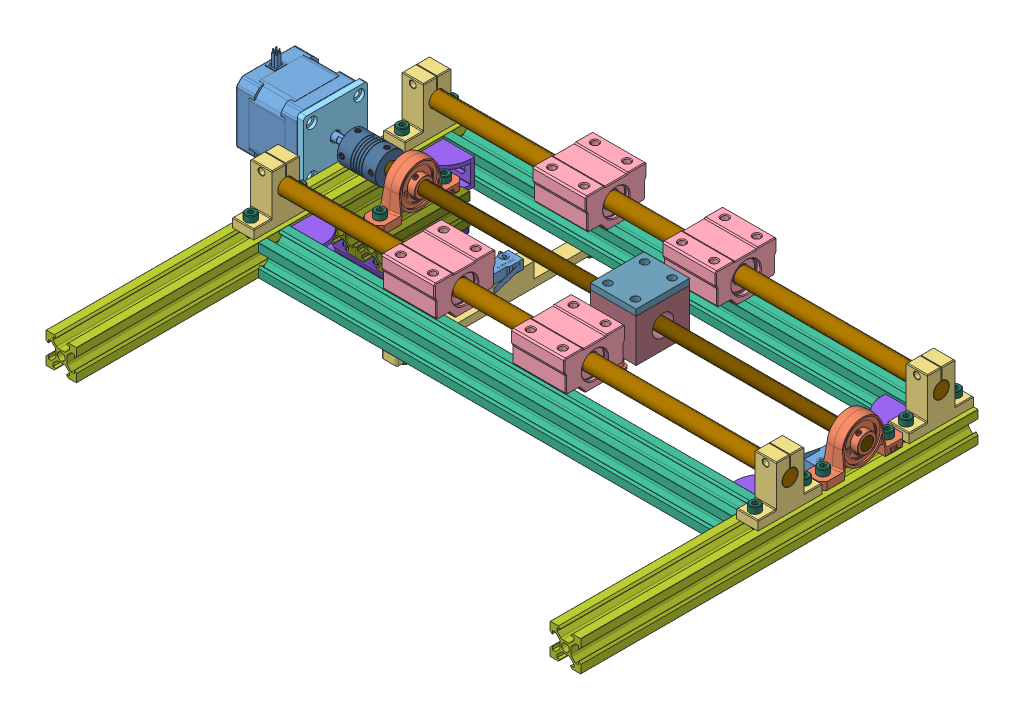
SolidWorks assembly eixox_assembly, configuration Default. Lengths in mm.
Overall size (394 74.2 260).
65 component instances, 21 part files, 147 mates.
Components (placement in the parent):
- motor_nema17_40mm-1: motor_nema17_40mm [По умолчанию] at (-339.1205 -27.1927 21.0547) x (0 0 1) z (0 1 0) size (42.3 62 51.35)
- Pillow Block P08-1: Pillow Block P08 [Default] at (44.8795 -27.1927 21.0547) x (0 0 -1) z (1 0 0) size (55 39.88 14.5)
- suporte_guia_sk10-1: suporte_guia_sk10 [Default] at (-292.1205 -32.4467 79.1336) x (0 0 -1) z (1 0 0) size (42 32.8 14)
- suporte_guia_sk10-2: suporte_guia_sk10 [Default] at (37.8795 -32.4467 -19.8664) x (0 0 -1) z (1 0 0) size (42 32.8 14)
- suporte_guia_sk10-3: suporte_guia_sk10 [Default] at (37.8795 -32.4467 79.1336) x (0 0 -1) z (1 0 0) size (42 32.8 14)
- suporte_guia_sk10-4: suporte_guia_sk10 [Default] at (-292.1205 -32.4467 -19.8664) x (0 0 -1) z (1 0 0) size (42 32.8 14)
- pillow_block_sc10uu-1: pillow_block_sc10uu [По умолчанию] at (-93.3361 -22.1927 -28.4453) x (0 0 1) z (1 0 0) size (40 26 35)
- pillow_block_sc10uu-2: pillow_block_sc10uu [По умолчанию] at (-178.3361 -22.1927 -28.4453) x (0 0 -1) z (-1 0 0) size (40 26 35)
- pillow_block_sc10uu-3: pillow_block_sc10uu [По умолчанию] at (-178.3361 -22.1927 70.5547) x (0 0 -1) z (-1 0 0) size (40 26 35)
- pillow_block_sc10uu-4: pillow_block_sc10uu [По умолчанию] at (-93.3361 -22.1927 70.5547) x (0 0 -1) z (-1 0 0) size (40 26 35)
- eixox_suporte_motor-1: eixox_suporte_motor [Default] at (-295.1205 -62.1927 0.0547) x (0 0 1) z (-1 0 0) size (42 56 4)
- eixox_superior_inferior-1: eixox_superior_inferior [Valor predeterminado] at (-275.1205 -52.1927 -39.4453) x (0 0 -1) z (1 0 0) size (20 20 310)
- eixox_superior_inferior-2: eixox_superior_inferior [Valor predeterminado] at (-275.1205 -52.1927 81.5547) x (0 0 -1) z (1 0 0) size (20 20 310)
- eixox_lateral-1: eixox_lateral [Valor predeterminado] at (-285.1205 -52.1927 -49.4453) size (20 20 260)
- eixox_lateral-2: eixox_lateral [Valor predeterminado] at (44.8795 -52.1927 -49.4453) size (20 20 260)
- cantoneira_perfil_2020-1: cantoneira_perfil_2020 [Varsayılan] at (34.8795 -52.1927 71.5547) x (-1 0 0) z (0 -1 0) size (20.5 20.5 17)
- cantoneira_perfil_2020-2: cantoneira_perfil_2020 [Varsayılan] at (-275.1205 -52.1927 71.5547) x (1 0 0) z (0 1 0) size (20.5 20.5 17)
- cantoneira_perfil_2020-3: cantoneira_perfil_2020 [Varsayılan] at (34.8795 -52.1927 -29.4453) x (-1 0 0) z (0 1 0) size (20.5 20.5 17)
- cantoneira_perfil_2020-4: cantoneira_perfil_2020 [Varsayılan] at (-275.1205 -52.1927 -29.4453) x (1 0 0) z (0 -1 0) size (20.5 20.5 17)
- eixox_eixo_linear-1: eixox_eixo_linear [Default] at (-292.1205 -22.1927 -28.4453) x (0 0.688665 0.725079) z (1 0 0) size (10 10 344)
- eixox_eixo_linear-2: eixox_eixo_linear [Default] at (-292.1205 -22.1927 70.5547) x (0 0 -1) z (1 0 0) size (10 10 344)
- Acople Flexible-2: Acople Flexible [Predeterminado] at (-284.1205 -28.6361 20.2939) x (0 -0.997299 0.073448) z (1 0 0) size (20.77 20.77 25)
  - Acople FlexibleSLDPRT-1: Acople FlexibleSLDPRT [Predeterminado] at (-1.3837 -0.8648 0) size (20.77 20.77 25)
  - socket set screw cone point_am-7: socket set screw cone point_am [B18.3.6M - M3 x 0.5 x 6 Hex Socket Cone Pt. SS --N] at (-11.2647 -0.8648 22) x (1 0 0) z (0 -0.164849 0.986319) size (6 3 3)
  - socket set screw cone point_am-8: socket set screw cone point_am [B18.3.6M - M3 x 0.5 x 6 Hex Socket Cone Pt. SS --N] at (-11.1909 -0.8648 3) x (1 0 0) z (0 0.00677 0.999977) size (6 3 3)
  - socket set screw cone point_am-9: socket set screw cone point_am [B18.3.6M - M3 x 0.5 x 6 Hex Socket Cone Pt. SS --N] at (-1.3837 -10.7654 3) x (0 1 0) z (-0.345086 0 0.938571) size (6 3 3)
  - socket set screw cone point_am-10: socket set screw cone point_am [B18.3.6M - M3 x 0.5 x 6 Hex Socket Cone Pt. SS --N] at (-1.3837 -10.5992 22) x (0 1 0) z (-0.865685 0 0.500588) size (6 3 3)
- castanha_tr8_2mm-2: castanha_tr8_2mm [Valor predeterminado] at (-106.8361 -27.1927 21.0547) x (0 -0.083617 0.996498) z (0 -0.996498 -0.083617) size (22 13.71 22)
- suporte_castanha_tr8-2: suporte_castanha_tr8 [Default] at (-80.8361 -41.1927 38.5547) x (0 0 -1) z (0 1 0) size (35 30 28)
- eixox_espacador_castanha-2: eixox_espacador_castanha [Default] at (-80.8361 -13.1927 38.5547) x (0 0 -1) z (0 1 0) size (35 30 4)
- socket head cap screw_am-1: socket head cap screw_am [B18.3.1M - 4 x 0.7 x 10 Hex SHCS -- 10NHX] at (-285.1205 -32.1927 -44.4453) x (0 -1 0) z (0 0 1) size (14 7 7)
- socket head cap screw_am-2: socket head cap screw_am [B18.3.1M - 4 x 0.7 x 10 Hex SHCS -- 10NHX] at (-285.1205 -32.1927 -12.4453) x (0 -1 0) z (0 0 1) size (14 7 7)
- socket head cap screw_am-3: socket head cap screw_am [B18.3.1M - 4 x 0.7 x 10 Hex SHCS -- 10NHX] at (-285.1205 -32.1927 54.5547) x (0 -1 0) z (0 0 1) size (14 7 7)
- socket head cap screw_am-4: socket head cap screw_am [B18.3.1M - 4 x 0.7 x 10 Hex SHCS -- 10NHX] at (-285.1205 -32.1927 86.5547) x (0 -1 0) z (0 0 1) size (14 7 7)
- socket head cap screw_am-5: socket head cap screw_am [B18.3.1M - 4 x 0.7 x 10 Hex SHCS -- 10NHX] at (44.8795 -32.1927 86.5547) x (0 -1 0) z (0 0 1) size (14 7 7)
- socket head cap screw_am-6: socket head cap screw_am [B18.3.1M - 4 x 0.7 x 10 Hex SHCS -- 10NHX] at (44.8795 -32.1927 54.5547) x (0 -1 0) z (0 0 1) size (14 7 7)
- socket head cap screw_am-7: socket head cap screw_am [B18.3.1M - 4 x 0.7 x 10 Hex SHCS -- 10NHX] at (44.8795 -33.1927 42.0547) x (0 -1 0) z (0 0 1) size (14 7 7)
- socket head cap screw_am-8: socket head cap screw_am [B18.3.1M - 4 x 0.7 x 10 Hex SHCS -- 10NHX] at (44.8795 -33.1927 0.0547) x (0 -1 0) z (0 0 1) size (14 7 7)
- socket head cap screw_am-9: socket head cap screw_am [B18.3.1M - 4 x 0.7 x 10 Hex SHCS -- 10NHX] at (44.8795 -32.1927 -12.4453) x (0 -1 0) z (0 0 1) size (14 7 7)
- socket head cap screw_am-10: socket head cap screw_am [B18.3.1M - 4 x 0.7 x 10 Hex SHCS -- 10NHX] at (44.8795 -32.1927 -44.4453) x (0 -1 0) z (0 0 1) size (14 7 7)
- socket head cap screw_am-11: socket head cap screw_am [B18.3.1M - 4 x 0.7 x 10 Hex SHCS -- 10NHX] at (-303.1205 -52.1927 10.5547) size (14 7 7)
- socket head cap screw_am-12: socket head cap screw_am [B18.3.1M - 4 x 0.7 x 10 Hex SHCS -- 10NHX] at (-303.1205 -52.1927 31.5547) size (14 7 7)
- eixox_perfil_suporte_mancal-1: eixox_perfil_suporte_mancal [Valor predeterminado] at (-265.1205 -52.1927 -6.9034) size (20 20 55)
- eixox_perfil_suporte_mancal-2: eixox_perfil_suporte_mancal [Valor predeterminado] at (-245.1205 -52.1927 -6.9034) size (20 20 55)
- Pillow Block P08-2: Pillow Block P08 [Default] at (-245.1205 -27.1927 21.0547) x (0 0 -1) z (1 0 0) size (55 39.88 14.5)
- eixox_chapa_suporte_mancal-1: eixox_chapa_suporte_mancal [Default] at (-295.1205 -66.1927 38.0966) x (0 0 1) z (0 1 0) size (10 60 4)
- eixox_chapa_suporte_mancal-2: eixox_chapa_suporte_mancal [Default] at (-295.1205 -62.1927 3.0966) x (0 0 -1) z (0 -1 0) size (10 60 4)
- socket head cap screw_am-15: socket head cap screw_am [B18.3.1M - 4 x 0.7 x 10 Hex SHCS -- 10NHX] at (-285.1205 -70.1927 -1.9034) x (0 1 0) z (0 0 1) size (14 7 7)
- socket head cap screw_am-16: socket head cap screw_am [B18.3.1M - 4 x 0.7 x 10 Hex SHCS -- 10NHX] at (-265.1205 -70.1927 -1.9034) x (0 1 0) z (0 0 1) size (14 7 7)
- socket head cap screw_am-17: socket head cap screw_am [B18.3.1M - 4 x 0.7 x 10 Hex SHCS -- 10NHX] at (-245.1205 -70.1927 -1.9034) x (0 1 0) z (0 0 1) size (14 7 7)
- socket head cap screw_am-18: socket head cap screw_am [B18.3.1M - 4 x 0.7 x 10 Hex SHCS -- 10NHX] at (-285.1205 -70.1927 43.0966) x (0 1 0) z (0 0 1) size (14 7 7)
- socket head cap screw_am-19: socket head cap screw_am [B18.3.1M - 4 x 0.7 x 10 Hex SHCS -- 10NHX] at (-265.1205 -70.1927 43.0966) x (0 1 0) z (0 0 1) size (14 7 7)
- socket head cap screw_am-20: socket head cap screw_am [B18.3.1M - 4 x 0.7 x 10 Hex SHCS -- 10NHX] at (-245.1205 -70.1927 43.0966) x (0 1 0) z (0 0 1) size (14 7 7)
- eixox_fuso-2: eixox_fuso [Default] at (-267.1705 -27.1927 21.0547) x (0 0.249209 0.96845) z (1 0 0) size (8 8 320)
- socket head cap screw_am-21: socket head cap screw_am [B18.3.1M - 4 x 0.7 x 10 Hex SHCS -- 10NHX] at (-245.1205 -33.1927 42.0547) x (0 -1 0) z (0 0 1) size (14 7 7)
- socket head cap screw_am-22: socket head cap screw_am [B18.3.1M - 4 x 0.7 x 10 Hex SHCS -- 10NHX] at (-245.1205 -33.1927 0.0547) x (0 -1 0) z (0 0 1) size (14 7 7)
- switch_fim_de_curso_KW11-3Z-5-1: switch_fim_de_curso_KW11-3Z-5 [Default] at (31.8955 -45.9927 31.9487) x (0 0 -1) z (-1 0 0) size (25.09 6.4 19.9)
- pan slot head_am-1: pan slot head_am [B18.6.7M - M3 x 0.5 x 20 Slotted PHMS --20N] at (-95.8361 -53.5927 33.5547) x (0 1 0) z (0 0 1) size (22.48 5.6 5.6)
- eixox_suporte_switch_fim_curso-1: eixox_suporte_switch_fim_curso [Default] at (22.7773 -62.1927 -49.4453) x (1 0 0) z (0 -1 0) size (10 141 15)
- eixox_suporte_switch_fim_curso-2: eixox_suporte_switch_fim_curso [Default] at (-184.407 -62.1927 91.5547) x (-1 0 0) z (0 -1 0) size (10 141 15)
- switch_fim_de_curso_KW11-3Z-5-2: switch_fim_de_curso_KW11-3Z-5 [Default] at (-193.5252 -51.9927 30.0606) x (0 0 -1) z (1 0 0) size (25.09 6.4 19.9)
- socket head cap screw_am-23: socket head cap screw_am [B18.3.1M - 4 x 0.7 x 10 Hex SHCS -- 10NHX] at (27.7773 -71.1927 -39.4453) x (0 1 0) z (0 0 1) size (14 7 7)
- socket head cap screw_am-24: socket head cap screw_am [B18.3.1M - 4 x 0.7 x 10 Hex SHCS -- 10NHX] at (27.7773 -71.1927 81.5547) x (0 1 0) z (0 0 1) size (14 7 7)
- socket head cap screw_am-25: socket head cap screw_am [B18.3.1M - 4 x 0.7 x 10 Hex SHCS -- 10NHX] at (-189.407 -71.1927 -39.4453) x (0 1 0) z (0 0 1) size (14 7 7)
- socket head cap screw_am-26: socket head cap screw_am [B18.3.1M - 4 x 0.7 x 10 Hex SHCS -- 10NHX] at (-189.407 -71.1927 81.5547) x (0 1 0) z (0 0 1) size (14 7 7)
Mates (geometry in assembly coordinates):
- Coincident9: coincident aligned: circle of suporte_guia_sk10-1; cylinder of suporte_guia_sk10-3 through (37.8795 -22.1927 70.5547) axis (1 0 0) radius 5
- Coincident11: coincident aligned: plane of suporte_guia_sk10-1 through (-278.1205 -36.1927 91.5547) normal (0 0 1); plane of suporte_guia_sk10-3 through (51.8795 -36.1927 91.5547) normal (0 0 1)
- Concentric5: concentric aligned: cylinder of suporte_guia_sk10-1 through (-292.1205 -22.1927 70.5547) axis (1 0 0) radius 5; cylinder of pillow_block_sc10uu-4 through (-107.8361 -22.1927 70.5547) axis (1 0 0) radius 5
- Concentric6: concentric aligned: cylinder of suporte_guia_sk10-1 through (-292.1205 -22.1927 70.5547) axis (1 0 0) radius 5; cylinder of pillow_block_sc10uu-3 through (-192.8361 -22.1927 70.5547) axis (1 0 0) radius 5
- Concentric7: concentric aligned: cylinder of suporte_guia_sk10-4 through (-292.1205 -22.1927 -28.4453) axis (1 0 0) radius 5; cylinder of pillow_block_sc10uu-2 through (-192.8361 -22.1927 -28.4453) axis (1 0 0) radius 5
- Coincident18: coincident aligned: plane of pillow_block_sc10uu-3 through (-195.8361 -9.1927 82.0024) normal (0 1 0); plane of pillow_block_sc10uu-4 through (-110.8361 -9.1927 82.0024) normal (0 1 0)
- Coincident19: coincident aligned: plane of pillow_block_sc10uu-1 through (-75.8361 -9.1927 -16.1337) normal (0 1 0); plane of pillow_block_sc10uu-2 through (-195.8361 -9.1927 -16.9976) normal (0 1 0)
- Concentric9: concentric aligned: cylinder of motor_nema17_40mm-1 through (-277.1205 -27.1927 21.0547) axis (-1 0 0) radius 2.5; circle of eixox_suporte_motor-1
- Coincident20: coincident anti-aligned: plane of motor_nema17_40mm-1 through (-299.1205 -27.1927 21.0547) normal (1 0 0); plane of eixox_suporte_motor-1 through (-299.1205 -62.1927 0.0547) normal (-1 0 0)
- Coincident21: coincident aligned: plane of motor_nema17_40mm-1 through (-299.1205 -6.1927 21.0547) normal (0 1 0); plane of eixox_suporte_motor-1 through (-299.1205 -6.1927 4.6831) normal (0 1 0)
- Coincident23: coincident aligned: plane of eixox_superior_inferior-1 through (34.8795 -61.9927 -49.4453) normal (0 0 -1); plane of eixox_lateral-1 through (-288.7034 -60.8927 -49.4453) normal (0 0 -1)
- Coincident37: coincident aligned: plane of eixox_superior_inferior-1 through (34.8795 -61.9927 -49.4453) normal (0 0 -1); plane of eixox_lateral-1 through (-288.7034 -60.8927 -49.4453) normal (0 0 -1)
- Coincident38: coincident anti-aligned: plane of eixox_superior_inferior-1 through (-275.1205 -60.8927 -35.8625) normal (-1 0 0); plane of eixox_lateral-1 through (-275.1205 -42.3927 210.5547) normal (1 0 0)
- Coincident39: coincident aligned: plane of eixox_superior_inferior-1 through (34.8795 -61.9927 -49.4453) normal (0 0 -1); plane of eixox_lateral-1 through (-288.7034 -60.8927 -49.4453) normal (0 0 -1)
- Coincident40: coincident aligned: plane of eixox_superior_inferior-1 through (34.8795 -42.1927 -44.0453) normal (0 1 0); plane of eixox_lateral-1 through (-280.5205 -42.1927 210.5547) normal (0 1 0)
- Coincident41: coincident aligned: plane of eixox_superior_inferior-1 through (34.8795 -42.1927 -44.0453) normal (0 1 0); plane of eixox_lateral-2 through (40.2795 -42.1927 210.5547) normal (0 1 0)
- Coincident42: coincident anti-aligned: plane of eixox_superior_inferior-1 through (34.8795 -60.8927 -35.8625) normal (1 0 0); plane of eixox_lateral-2 through (34.8795 -42.3927 210.5547) normal (-1 0 0)
- Coincident43: coincident aligned: plane of eixox_superior_inferior-1 through (34.8795 -61.9927 -49.4453) normal (0 0 -1); plane of eixox_lateral-2 through (41.2966 -60.8927 -49.4453) normal (0 0 -1)
- Coincident44: coincident anti-aligned: plane of eixox_superior_inferior-2 through (34.8795 -60.8927 85.1375) normal (1 0 0); plane of eixox_lateral-2 through (34.8795 -61.9927 210.5547) normal (-1 0 0)
- Coincident45: coincident aligned: plane of eixox_superior_inferior-2 through (34.8795 -42.1927 76.9547) normal (0 1 0); plane of eixox_lateral-2 through (40.2795 -42.1927 210.5547) normal (0 1 0)
- Distance2: distance = 3 mm aligned: plane of suporte_guia_sk10-1 through (-292.1205 -32.4467 79.1336) normal (-1 0 0); plane of eixox_lateral-1 through (-295.1205 -42.3927 210.5547) normal (-1 0 0)
- Coincident47: coincident aligned: plane of suporte_guia_sk10-1 through (-292.1205 -32.4467 79.1336) normal (-1 0 0); plane of suporte_guia_sk10-4 through (-292.1205 -32.4467 -19.8664) normal (-1 0 0)
- Coincident51: coincident anti-aligned: plane of suporte_guia_sk10-3 through (51.8795 -42.1927 91.5547) normal (0 -1 0); plane of eixox_lateral-2 through (49.4795 -42.1927 210.5547) normal (0 1 0)
- Coincident57: coincident anti-aligned: plane of suporte_guia_sk10-4 through (-278.1205 -42.1927 -7.4453) normal (0 -1 0); plane of eixox_lateral-1 through (-280.5205 -42.1927 210.5547) normal (0 1 0)
- Coincident58: coincident anti-aligned: plane of suporte_guia_sk10-2 through (51.8795 -42.1927 -7.4453) normal (0 -1 0); plane of eixox_lateral-2 through (49.4795 -42.1927 210.5547) normal (0 1 0)
- Concentric11: concentric anti-aligned: cylinder of pillow_block_sc10uu-1 through (-78.8361 -22.1927 -28.4453) axis (-1 0 0) radius 5; cylinder of pillow_block_sc10uu-2 through (-192.8361 -22.1927 -28.4453) axis (1 0 0) radius 5
- Concentric12: concentric anti-aligned: cylinder of suporte_guia_sk10-2 through (37.8795 -22.1927 -28.4453) axis (1 0 0) radius 5; cylinder of pillow_block_sc10uu-1 through (-78.8361 -22.1927 -28.4453) axis (-1 0 0) radius 5
- Coincident59: coincident aligned: plane of suporte_guia_sk10-2 through (51.8795 -32.4467 -19.8664) normal (1 0 0); plane of suporte_guia_sk10-3 through (51.8795 -32.4467 79.1336) normal (1 0 0)
- Distance4: distance = 3 mm aligned: plane of suporte_guia_sk10-2 through (51.8795 -32.4467 -19.8664) normal (1 0 0); plane of eixox_lateral-2 through (54.8795 -42.3927 210.5547) normal (1 0 0)
- Coincident61: coincident anti-aligned: plane of eixox_suporte_motor-1 through (-295.1205 -62.1927 0.0547) normal (1 0 0); plane of eixox_lateral-1 through (-295.1205 -61.9927 210.5547) normal (-1 0 0)
- Coincident62: coincident aligned: plane of eixox_suporte_motor-1 through (-299.1205 -62.1927 0.0547) normal (0 -1 0); plane of eixox_lateral-1 through (-289.7205 -62.1927 210.5547) normal (0 -1 0)
- Coincident65: coincident anti-aligned: plane of Pillow Block P08-1 through (44.8795 -42.1927 21.0547) normal (0 -1 0); plane of eixox_lateral-2 through (49.4795 -42.1927 210.5547) normal (0 1 0)
- Distance5: distance = 3.5 mm aligned: plane of Pillow Block P08-1 through (51.3795 -27.1927 21.0547) normal (1 0 0); plane of eixox_lateral-2 through (54.8795 -42.3927 210.5547) normal (1 0 0)
- Coincident69: coincident aligned: plane of pillow_block_sc10uu-2 through (-195.8361 -9.1927 -40.7569) normal (0 1 0); plane of pillow_block_sc10uu-3 through (-195.8361 -9.1927 58.2431) normal (0 1 0)
- Coincident70: coincident aligned: plane of pillow_block_sc10uu-1 through (-75.8361 -9.1927 -39.893) normal (0 1 0); plane of pillow_block_sc10uu-2 through (-195.8361 -9.1927 -40.7569) normal (0 1 0)
- Coincident72: coincident aligned: plane of suporte_guia_sk10-2 through (51.8795 -36.1927 -49.4453) normal (0 0 -1); plane of eixox_lateral-2 through (41.2966 -60.8927 -49.4453) normal (0 0 -1)
- Coincident73: coincident aligned: plane of pillow_block_sc10uu-1 through (-75.8361 -22.1927 -28.4453) normal (1 0 0); plane of pillow_block_sc10uu-4 through (-75.8361 -22.1927 70.5547) normal (1 0 0)
- Coincident74: coincident aligned: plane of pillow_block_sc10uu-2 through (-160.8361 -22.1927 -28.4453) normal (1 0 0); plane of pillow_block_sc10uu-3 through (-160.8361 -22.1927 70.5547) normal (1 0 0)
- Concentric15: concentric aligned: cylinder of motor_nema17_40mm-1 through (-277.1205 -27.1927 21.0547) axis (-1 0 0) radius 2.5; cylinder of Pillow Block P08-1 through (36.6423 -27.1927 21.0547) axis (-1 0 0) radius 4
- Distance7: distance = 1 mm anti-aligned: plane of suporte_guia_sk10-2 through (51.8795 -36.1927 -7.4453) normal (0 0 1); plane of Pillow Block P08-1 through (51.3795 -27.1927 -6.4453) normal (0 0 -1)
- Distance8: distance = 1 mm anti-aligned: plane of suporte_guia_sk10-3 through (51.8795 -36.1927 49.5547) normal (0 0 -1); plane of Pillow Block P08-1 through (51.3795 -27.1927 48.5547) normal (0 0 1)
- Coincident77: coincident anti-aligned: plane of eixox_lateral-2 through (34.8795 -42.3927 210.5547) normal (-1 0 0); plane of cantoneira_perfil_2020-3 through (34.8795 -43.6927 -29.4453) normal (1 0 0)
- Coincident79: coincident anti-aligned: plane of eixox_superior_inferior-1 through (34.8795 -42.3927 -29.4453) normal (0 0 1); plane of cantoneira_perfil_2020-3 through (14.3795 -43.6927 -29.4453) normal (0 0 -1)
- Coincident80: coincident aligned: plane of cantoneira_perfil_2020-3 through (34.8795 -43.6927 -29.4453) normal (0 1 0); plane of cantoneira_perfil_2020-4 through (-275.1205 -43.6927 -29.4453) normal (0 1 0)
- Coincident81: coincident anti-aligned: plane of eixox_lateral-1 through (-275.1205 -42.3927 210.5547) normal (1 0 0); plane of cantoneira_perfil_2020-4 through (-275.1205 -60.6927 -29.4453) normal (-1 0 0)
- Coincident84: coincident anti-aligned: plane of eixox_superior_inferior-2 through (34.8795 -42.3927 71.5547) normal (0 0 -1); plane of cantoneira_perfil_2020-1 through (14.3795 -60.6927 71.5547) normal (0 0 1)
- Coincident85: coincident anti-aligned: plane of eixox_lateral-2 through (34.8795 -42.3927 210.5547) normal (-1 0 0); plane of cantoneira_perfil_2020-1 through (34.8795 -60.6927 71.5547) normal (1 0 0)
- Coincident86: coincident anti-aligned: plane of eixox_superior_inferior-2 through (34.8795 -42.3927 71.5547) normal (0 0 -1); plane of cantoneira_perfil_2020-2 through (-254.6205 -43.6927 71.5547) normal (0 0 1)
- Coincident87: coincident anti-aligned: plane of eixox_lateral-1 through (-275.1205 -42.3927 210.5547) normal (1 0 0); plane of cantoneira_perfil_2020-2 through (-275.1205 -43.6927 71.5547) normal (-1 0 0)
- Coincident88: coincident aligned: plane of cantoneira_perfil_2020-1 through (34.8795 -43.6927 71.5547) normal (0 1 0); plane of cantoneira_perfil_2020-2 through (-275.1205 -43.6927 71.5547) normal (0 1 0)
- Coincident89: coincident aligned: plane of cantoneira_perfil_2020-1 through (34.8795 -43.6927 71.5547) normal (0 1 0); plane of cantoneira_perfil_2020-3 through (34.8795 -43.6927 -29.4453) normal (0 1 0)
- Distance9: distance = 1.5 mm aligned: plane of cantoneira_perfil_2020-4 through (-275.1205 -43.6927 -29.4453) normal (0 1 0); plane of eixox_superior_inferior-1 through (34.8795 -42.1927 -34.8453) normal (0 1 0)
- Coincident91: coincident anti-aligned: plane of eixox_superior_inferior-1 through (34.8795 -42.3927 -29.4453) normal (0 0 1); plane of cantoneira_perfil_2020-4 through (-254.6205 -60.6927 -29.4453) normal (0 0 -1)
- Coincident92: coincident aligned: plane of suporte_guia_sk10-1 through (-278.1205 -36.1927 91.5547) normal (0 0 1); plane of eixox_superior_inferior-2 through (34.8795 -42.3927 91.5547) normal (0 0 1)
- Concentric16: concentric anti-aligned: cylinder of suporte_guia_sk10-1 through (-292.1205 -22.1927 70.5547) axis (1 0 0) radius 5; cylinder of eixox_eixo_linear-2 through (51.8795 -22.1927 70.5547) axis (-1 0 0) radius 5
- Concentric17: concentric anti-aligned: cylinder of suporte_guia_sk10-4 through (-292.1205 -22.1927 -28.4453) axis (1 0 0) radius 5; cylinder of eixox_eixo_linear-1 through (51.8795 -22.1927 -28.4453) axis (-1 0 0) radius 5
- Coincident93: coincident aligned: plane of eixox_eixo_linear-1 through (-292.1205 -22.1927 -28.4453) normal (-1 0 0); plane of eixox_eixo_linear-2 through (-292.1205 -22.1927 70.5547) normal (-1 0 0)
- Coincident94: coincident aligned: plane of suporte_guia_sk10-1 through (-292.1205 -32.4467 79.1336) normal (-1 0 0); plane of eixox_eixo_linear-2 through (-292.1205 -22.1927 70.5547) normal (-1 0 0)
- Concentric18: concentric aligned: cylinder of motor_nema17_40mm-1 through (-277.1205 -27.1927 21.0547) axis (-1 0 0) radius 2.5; cylinder of Acople Flexible-2/Acople FlexibleSLDPRT-1 through (-259.1205 -27.1927 21.0547) axis (-1 0 0) radius 2.5
- Distance10: distance = 8 mm anti-aligned: plane of motor_nema17_40mm-1 through (-292.1205 -27.1927 21.0547) normal (1 0 0); plane of Acople Flexible-2/Acople FlexibleSLDPRT-1 through (-284.1205 -27.1927 21.0547) normal (-1 0 0)
- Concentric19: concentric anti-aligned: cylinder of castanha_tr8_2mm-2 through (-96.8361 -27.1927 21.0547) axis (-1 0 0) radius 5; cylinder of suporte_castanha_tr8-2 through (-138.8361 -27.1927 21.0547) axis (1 0 0) radius 6
- Coincident97: coincident anti-aligned: plane of castanha_tr8_2mm-2 through (-106.8361 -27.1927 21.0547) normal (1 0 0); plane of suporte_castanha_tr8-2 through (-106.8361 -27.1927 21.0547) normal (-1 0 0)
- Concentric20: concentric aligned: cylinder of Acople Flexible-2/Acople FlexibleSLDPRT-1 through (-277.1205 -27.1927 21.0547) axis (1 0 0) radius 4; cylinder of suporte_castanha_tr8-2 through (-88.8361 -27.1927 21.0547) axis (1 0 0) radius 7
- Coincident98: coincident anti-aligned: plane of suporte_castanha_tr8-2 through (-80.8361 -13.1927 38.5547) normal (0 1 0); plane of eixox_espacador_castanha-2 through (-80.8361 -13.1927 38.5547) normal (0 -1 0)
- Coincident99: coincident aligned: plane of suporte_castanha_tr8-2 through (-80.8361 -13.1927 38.5547) normal (1 0 0); plane of eixox_espacador_castanha-2 through (-80.8361 -9.1927 38.5547) normal (1 0 0)
- Coincident100: coincident aligned: plane of suporte_castanha_tr8-2 through (-80.8361 -13.1927 38.5547) normal (0 0 1); plane of eixox_espacador_castanha-2 through (-80.8361 -9.1927 38.5547) normal (0 0 1)
- Parallel6: parallel aligned: plane of pillow_block_sc10uu-3 through (-195.8361 -9.6927 70.5607) normal (0 1 0); plane of eixox_espacador_castanha-2 through (-80.8361 -9.1927 38.5547) normal (0 1 0)
- Coincident104: coincident aligned: plane of pillow_block_sc10uu-2 through (-195.8361 -9.6927 -28.4393) normal (0 1 0); plane of pillow_block_sc10uu-3 through (-195.8361 -9.6927 70.5607) normal (0 1 0)
- Distance11: distance = 120 mm anti-aligned: plane of pillow_block_sc10uu-1 through (-75.8361 -22.1927 -28.4453) normal (1 0 0); plane of pillow_block_sc10uu-2 through (-195.8361 -22.1927 -28.4453) normal (-1 0 0)
- Distance12: distance = 5 mm aligned: plane of suporte_castanha_tr8-2 through (-80.8361 -13.1927 38.5547) normal (1 0 0); plane of pillow_block_sc10uu-1 through (-75.8361 -22.1927 -28.4453) normal (1 0 0)
- Concentric21: concentric anti-aligned: cone of suporte_guia_sk10-4 through (-285.1205 -36.6927 -44.4453) axis (0 -1 0); cylinder of socket head cap screw_am-1 through (-285.1205 -0.4427 -44.4453) axis (0 1 0) radius 3.5
- Coincident107: coincident anti-aligned: plane of suporte_guia_sk10-4 through (-278.1205 -36.1927 -37.4453) normal (0 1 0); plane of socket head cap screw_am-1 through (-281.6205 -36.1927 -44.4453) normal (0 -1 0)
- Concentric22: concentric anti-aligned: cone of suporte_guia_sk10-4 through (-285.1205 -36.6927 -12.4453) axis (0 -1 0); cylinder of socket head cap screw_am-2 through (-285.1205 -0.4427 -12.4453) axis (0 1 0) radius 3.5
- Coincident108: coincident anti-aligned: plane of suporte_guia_sk10-4 through (-278.1205 -36.1927 -7.4453) normal (0 1 0); plane of socket head cap screw_am-2 through (-281.6205 -36.1927 -12.4453) normal (0 -1 0)
- Concentric23: concentric anti-aligned: cone of suporte_guia_sk10-1 through (-285.1205 -36.6927 54.5547) axis (0 -1 0); cylinder of socket head cap screw_am-3 through (-285.1205 -0.4427 54.5547) axis (0 1 0) radius 3.5
- Coincident109: coincident anti-aligned: plane of suporte_guia_sk10-1 through (-278.1205 -36.1927 61.5547) normal (0 1 0); plane of socket head cap screw_am-3 through (-281.6205 -36.1927 54.5547) normal (0 -1 0)
- Concentric24: concentric anti-aligned: cone of suporte_guia_sk10-1 through (-285.1205 -36.6927 86.5547) axis (0 -1 0); cylinder of socket head cap screw_am-4 through (-285.1205 -0.4427 86.5547) axis (0 1 0) radius 3.5
- Coincident110: coincident anti-aligned: plane of suporte_guia_sk10-1 through (-278.1205 -36.1927 91.5547) normal (0 1 0); plane of socket head cap screw_am-4 through (-281.6205 -36.1927 86.5547) normal (0 -1 0)
- Concentric25: concentric anti-aligned: cone of suporte_guia_sk10-3 through (44.8795 -36.6927 86.5547) axis (0 -1 0); cylinder of socket head cap screw_am-5 through (44.8795 -0.4427 86.5547) axis (0 1 0) radius 3.5
- Coincident111: coincident anti-aligned: plane of suporte_guia_sk10-3 through (51.8795 -36.1927 91.5547) normal (0 1 0); plane of socket head cap screw_am-5 through (48.3795 -36.1927 86.5547) normal (0 -1 0)
- Concentric26: concentric anti-aligned: cone of suporte_guia_sk10-3 through (44.8795 -36.6927 54.5547) axis (0 -1 0); cylinder of socket head cap screw_am-6 through (44.8795 -0.4427 54.5547) axis (0 1 0) radius 3.5
- Coincident112: coincident anti-aligned: plane of suporte_guia_sk10-3 through (51.8795 -36.1927 61.5547) normal (0 1 0); plane of socket head cap screw_am-6 through (48.3795 -36.1927 54.5547) normal (0 -1 0)
- Concentric27: concentric aligned: cylinder of Pillow Block P08-1 through (44.8795 -43.1927 42.0547) axis (0 1 0) radius 2.5; cylinder of socket head cap screw_am-7 through (44.8795 -1.4427 42.0547) axis (0 1 0) radius 3.5
- Coincident113: coincident anti-aligned: plane of Pillow Block P08-1 through (51.3795 -37.1927 21.0547) normal (0 1 0); plane of socket head cap screw_am-7 through (48.3795 -37.1927 42.0547) normal (0 -1 0)
- Concentric28: concentric aligned: cylinder of Pillow Block P08-1 through (44.8795 -43.1927 0.0547) axis (0 1 0) radius 2.5; cylinder of socket head cap screw_am-8 through (44.8795 -1.4427 0.0547) axis (0 1 0) radius 3.5
- Coincident114: coincident anti-aligned: plane of Pillow Block P08-1 through (51.3795 -37.1927 21.0547) normal (0 1 0); plane of socket head cap screw_am-8 through (48.3795 -37.1927 0.0547) normal (0 -1 0)
- Concentric29: concentric anti-aligned: cone of suporte_guia_sk10-2 through (44.8795 -36.6927 -12.4453) axis (0 -1 0); cylinder of socket head cap screw_am-9 through (44.8795 -0.4427 -12.4453) axis (0 1 0) radius 3.5
- Coincident115: coincident anti-aligned: plane of suporte_guia_sk10-2 through (51.8795 -36.1927 -7.4453) normal (0 1 0); plane of socket head cap screw_am-9 through (48.3795 -36.1927 -12.4453) normal (0 -1 0)
- Concentric30: concentric anti-aligned: cone of suporte_guia_sk10-2 through (44.8795 -36.6927 -44.4453) axis (0 -1 0); cylinder of socket head cap screw_am-10 through (44.8795 -0.4427 -44.4453) axis (0 1 0) radius 3.5
- Coincident116: coincident anti-aligned: plane of suporte_guia_sk10-2 through (51.8795 -36.1927 -37.4453) normal (0 1 0); plane of socket head cap screw_am-10 through (48.3795 -36.1927 -44.4453) normal (0 -1 0)
- Concentric31: concentric aligned: cylinder of eixox_suporte_motor-1 through (-289.1205 -52.1927 10.5547) axis (-1 0 0) radius 2.5; cylinder of socket head cap screw_am-11 through (-334.8705 -52.1927 10.5547) axis (-1 0 0) radius 3.5
- Coincident117: coincident anti-aligned: plane of eixox_suporte_motor-1 through (-299.1205 -62.1927 0.0547) normal (-1 0 0); plane of socket head cap screw_am-11 through (-299.1205 -48.6927 10.5547) normal (1 0 0)
- Concentric32: concentric aligned: cylinder of eixox_suporte_motor-1 through (-289.1205 -52.1927 31.5547) axis (-1 0 0) radius 2.5; cylinder of socket head cap screw_am-12 through (-334.8705 -52.1927 31.5547) axis (-1 0 0) radius 3.5
- Coincident118: coincident anti-aligned: plane of eixox_suporte_motor-1 through (-299.1205 -62.1927 0.0547) normal (-1 0 0); plane of socket head cap screw_am-12 through (-299.1205 -48.6927 31.5547) normal (1 0 0)
- Coincident119: coincident aligned: plane of eixox_perfil_suporte_mancal-1 through (-260.5205 -42.1927 48.0966) normal (0 1 0); plane of eixox_perfil_suporte_mancal-2 through (-249.7205 -42.1927 48.0966) normal (0 1 0)
- Coincident120: coincident anti-aligned: plane of eixox_perfil_suporte_mancal-1 through (-255.1205 -42.3927 48.0966) normal (1 0 0); plane of eixox_perfil_suporte_mancal-2 through (-255.1205 -42.3927 48.0966) normal (-1 0 0)
- Coincident121: coincident aligned: plane of eixox_perfil_suporte_mancal-1 through (-268.7034 -60.8927 -6.9034) normal (0 0 -1); plane of eixox_perfil_suporte_mancal-2 through (-248.7034 -60.8927 -6.9034) normal (0 0 -1)
- Coincident122: coincident aligned: plane of eixox_lateral-1 through (-280.5205 -42.1927 210.5547) normal (0 1 0); plane of eixox_perfil_suporte_mancal-1 through (-269.7205 -42.1927 48.0966) normal (0 1 0)
- Coincident123: coincident anti-aligned: plane of eixox_lateral-1 through (-275.1205 -42.3927 210.5547) normal (1 0 0); plane of eixox_perfil_suporte_mancal-1 through (-275.1205 -42.3927 48.0966) normal (-1 0 0)
- Concentric33: concentric anti-aligned: cylinder of Acople Flexible-2/Acople FlexibleSLDPRT-1 through (-277.1205 -27.1927 21.0547) axis (1 0 0) radius 4; cylinder of Pillow Block P08-2 through (-253.3577 -27.1927 21.0547) axis (-1 0 0) radius 4
- Coincident124: coincident anti-aligned: plane of eixox_perfil_suporte_mancal-2 through (-240.5205 -42.1927 48.0966) normal (0 1 0); plane of Pillow Block P08-2 through (-245.1205 -42.1927 21.0547) normal (0 -1 0)
- Distance13: distance = 3.5 mm aligned: plane of Pillow Block P08-2 through (-238.6205 -27.1927 21.0547) normal (1 0 0); plane of eixox_perfil_suporte_mancal-2 through (-235.1205 -61.9927 48.0966) normal (1 0 0)
- Coincident126: coincident aligned: plane of eixox_chapa_suporte_mancal-1 through (-295.1205 -62.1927 38.0966) normal (0 1 0); plane of eixox_chapa_suporte_mancal-2 through (-295.1205 -62.1927 3.0966) normal (0 1 0)
- Coincident127: coincident aligned: plane of eixox_chapa_suporte_mancal-1 through (-295.1205 -62.1927 38.0966) normal (-1 0 0); plane of eixox_chapa_suporte_mancal-2 through (-295.1205 -66.1927 3.0966) normal (-1 0 0)
- Coincident128: coincident anti-aligned: plane of eixox_lateral-1 through (-280.5205 -62.1927 210.5547) normal (0 -1 0); plane of eixox_chapa_suporte_mancal-2 through (-295.1205 -62.1927 3.0966) normal (0 1 0)
- Coincident129: coincident aligned: plane of eixox_perfil_suporte_mancal-1 through (-268.7034 -60.8927 -6.9034) normal (0 0 -1); plane of eixox_chapa_suporte_mancal-2 through (-295.1205 -66.1927 -6.9034) normal (0 0 -1)
- Coincident130: coincident aligned: plane of eixox_perfil_suporte_mancal-1 through (-268.7034 -60.8927 48.0966) normal (0 0 1); plane of eixox_chapa_suporte_mancal-1 through (-295.1205 -62.1927 48.0966) normal (0 0 1)
- Coincident131: coincident aligned: plane of eixox_lateral-1 through (-295.1205 -61.9927 210.5547) normal (-1 0 0); plane of eixox_chapa_suporte_mancal-1 through (-295.1205 -62.1927 38.0966) normal (-1 0 0)
- Concentric34: concentric anti-aligned: cylinder of eixox_chapa_suporte_mancal-2 through (-285.1205 -66.1927 -1.9034) axis (0 1 0) radius 2.5; cylinder of socket head cap screw_am-15 through (-285.1205 -101.9427 -1.9034) axis (0 -1 0) radius 3.5
- Coincident132: coincident anti-aligned: plane of eixox_chapa_suporte_mancal-2 through (-295.1205 -66.1927 3.0966) normal (0 -1 0); plane of socket head cap screw_am-15 through (-288.6205 -66.1927 -1.9034) normal (0 1 0)
- Concentric35: concentric anti-aligned: cylinder of eixox_chapa_suporte_mancal-2 through (-265.1205 -66.1927 -1.9034) axis (0 1 0) radius 2.5; cylinder of socket head cap screw_am-16 through (-265.1205 -101.9427 -1.9034) axis (0 -1 0) radius 3.5
- Coincident133: coincident anti-aligned: plane of eixox_chapa_suporte_mancal-2 through (-295.1205 -66.1927 3.0966) normal (0 -1 0); plane of socket head cap screw_am-16 through (-268.6205 -66.1927 -1.9034) normal (0 1 0)
- Concentric36: concentric anti-aligned: cylinder of eixox_chapa_suporte_mancal-2 through (-245.1205 -66.1927 -1.9034) axis (0 1 0) radius 2.5; cylinder of socket head cap screw_am-17 through (-245.1205 -101.9427 -1.9034) axis (0 -1 0) radius 3.5
- Coincident134: coincident anti-aligned: plane of eixox_chapa_suporte_mancal-2 through (-295.1205 -66.1927 3.0966) normal (0 -1 0); plane of socket head cap screw_am-17 through (-248.6205 -66.1927 -1.9034) normal (0 1 0)
- Concentric37: concentric aligned: cylinder of eixox_chapa_suporte_mancal-1 through (-285.1205 -62.1927 43.0966) axis (0 -1 0) radius 2.5; cylinder of socket head cap screw_am-18 through (-285.1205 -101.9427 43.0966) axis (0 -1 0) radius 3.5
- Coincident135: coincident anti-aligned: plane of eixox_chapa_suporte_mancal-1 through (-295.1205 -66.1927 38.0966) normal (0 -1 0); plane of socket head cap screw_am-18 through (-288.6205 -66.1927 43.0966) normal (0 1 0)
- Concentric38: concentric aligned: cylinder of eixox_chapa_suporte_mancal-1 through (-265.1205 -62.1927 43.0966) axis (0 -1 0) radius 2.5; cylinder of socket head cap screw_am-19 through (-265.1205 -101.9427 43.0966) axis (0 -1 0) radius 3.5
- Coincident136: coincident anti-aligned: plane of eixox_chapa_suporte_mancal-1 through (-295.1205 -66.1927 38.0966) normal (0 -1 0); plane of socket head cap screw_am-19 through (-268.6205 -66.1927 43.0966) normal (0 1 0)
- Concentric39: concentric aligned: cylinder of eixox_chapa_suporte_mancal-1 through (-245.1205 -62.1927 43.0966) axis (0 -1 0) radius 2.5; cylinder of socket head cap screw_am-20 through (-245.1205 -101.9427 43.0966) axis (0 -1 0) radius 3.5
- Coincident137: coincident anti-aligned: plane of eixox_chapa_suporte_mancal-1 through (-295.1205 -66.1927 38.0966) normal (0 -1 0); plane of socket head cap screw_am-20 through (-248.6205 -66.1927 43.0966) normal (0 1 0)
- Concentric40: concentric anti-aligned: cylinder of Acople Flexible-2/Acople FlexibleSLDPRT-1 through (-277.1205 -27.1927 21.0547) axis (1 0 0) radius 4; cylinder of eixox_fuso-2 through (52.8295 -27.1927 21.0547) axis (-1 0 0) radius 4
- Coincident138: coincident aligned: plane of Pillow Block P08-1 through (52.8295 -28.8437 24.6981) normal (1 0 0); plane of eixox_fuso-2 through (52.8295 -27.1927 21.0547) normal (1 0 0)
- Concentric41: concentric aligned: cylinder of Pillow Block P08-2 through (-245.1205 -43.1927 42.0547) axis (0 1 0) radius 2.5; cylinder of socket head cap screw_am-21 through (-245.1205 -1.4427 42.0547) axis (0 1 0) radius 3.5
- Coincident139: coincident anti-aligned: plane of Pillow Block P08-2 through (-238.6205 -37.1927 21.0547) normal (0 1 0); plane of socket head cap screw_am-21 through (-241.6205 -37.1927 42.0547) normal (0 -1 0)
- Concentric42: concentric aligned: cylinder of Pillow Block P08-2 through (-245.1205 -43.1927 0.0547) axis (0 1 0) radius 2.5; cylinder of socket head cap screw_am-22 through (-245.1205 -1.4427 0.0547) axis (0 1 0) radius 3.5
- Coincident140: coincident anti-aligned: plane of Pillow Block P08-2 through (-238.6205 -37.1927 21.0547) normal (0 1 0); plane of socket head cap screw_am-22 through (-241.6205 -37.1927 0.0547) normal (0 -1 0)
- LimitDistance2: limit distance = 82.2844 mm anti-aligned: plane of pillow_block_sc10uu-2 through (-195.8361 -22.1927 -28.4453) normal (-1 0 0); plane of suporte_guia_sk10-4 through (-278.1205 -32.4467 -19.8664) normal (1 0 0)
- Coincident141: coincident anti-aligned: plane of suporte_castanha_tr8-2 through (-95.8361 -31.1927 33.5547) normal (0 -1 0); plane of pan slot head_am-1 through (-97.3361 -31.1927 33.5547) normal (0 1 0)
- Concentric43: concentric aligned: cylinder of suporte_castanha_tr8-2 through (-95.8361 -31.1927 33.5547) axis (0 -1 0) radius 1.5; cylinder of pan slot head_am-1 through (-95.8361 -78.9927 33.5547) axis (0 -1 0) radius 1.5
- Coincident142: coincident anti-aligned: plane of eixox_superior_inferior-1 through (34.8795 -62.1927 -44.0453) normal (0 -1 0); plane of eixox_suporte_switch_fim_curso-1 through (22.7773 -62.1927 -49.4453) normal (0 1 0)
- Coincident143: coincident aligned: plane of eixox_superior_inferior-1 through (34.8795 -61.9927 -49.4453) normal (0 0 -1); plane of eixox_suporte_switch_fim_curso-1 through (22.7773 -67.1927 -49.4453) normal (0 0 -1)
- Coincident145: coincident aligned: plane of eixox_superior_inferior-1 through (34.8795 -61.9927 -49.4453) normal (0 0 -1); plane of eixox_suporte_switch_fim_curso-2 through (-184.407 -67.1927 -49.4453) normal (0 0 -1)
- Coincident150: coincident anti-aligned: plane of switch_fim_de_curso_KW11-3Z-5-1 through (31.8955 -52.1927 31.9487) normal (0 -1 0); plane of eixox_suporte_switch_fim_curso-1 through (22.7773 -52.1927 -49.4453) normal (0 1 0)
- Concentric44: concentric anti-aligned: cylinder of eixox_suporte_switch_fim_curso-1 through (27.7773 -67.1927 -39.4453) axis (0 1 0) radius 2.5; cylinder of socket head cap screw_am-23 through (27.7773 -102.9427 -39.4453) axis (0 -1 0) radius 3.5
- Coincident151: coincident anti-aligned: plane of eixox_suporte_switch_fim_curso-1 through (22.7773 -67.1927 -49.4453) normal (0 -1 0); plane of socket head cap screw_am-23 through (24.2773 -67.1927 -39.4453) normal (0 1 0)
- Concentric45: concentric anti-aligned: cylinder of eixox_suporte_switch_fim_curso-1 through (27.7773 -67.1927 81.5547) axis (0 1 0) radius 2.5; cylinder of socket head cap screw_am-24 through (27.7773 -102.9427 81.5547) axis (0 -1 0) radius 3.5
- Coincident152: coincident anti-aligned: plane of eixox_suporte_switch_fim_curso-1 through (22.7773 -67.1927 -49.4453) normal (0 -1 0); plane of socket head cap screw_am-24 through (24.2773 -67.1927 81.5547) normal (0 1 0)
- Coincident153: coincident anti-aligned: plane of eixox_superior_inferior-1 through (34.8795 -62.1927 -44.0453) normal (0 -1 0); plane of eixox_suporte_switch_fim_curso-2 through (-184.407 -62.1927 91.5547) normal (0 1 0)
- Concentric46: concentric anti-aligned: cylinder of eixox_suporte_switch_fim_curso-2 through (-189.407 -67.1927 -39.4453) axis (0 1 0) radius 2.5; cylinder of socket head cap screw_am-25 through (-189.407 -102.9427 -39.4453) axis (0 -1 0) radius 3.5
- Coincident154: coincident anti-aligned: plane of eixox_suporte_switch_fim_curso-2 through (-184.407 -67.1927 91.5547) normal (0 -1 0); plane of socket head cap screw_am-25 through (-192.907 -67.1927 -39.4453) normal (0 1 0)
- Concentric47: concentric anti-aligned: cylinder of eixox_suporte_switch_fim_curso-2 through (-189.407 -67.1927 81.5547) axis (0 1 0) radius 2.5; cylinder of socket head cap screw_am-26 through (-189.407 -102.9427 81.5547) axis (0 -1 0) radius 3.5
- Coincident155: coincident anti-aligned: plane of eixox_suporte_switch_fim_curso-2 through (-184.407 -67.1927 91.5547) normal (0 -1 0); plane of socket head cap screw_am-26 through (-192.907 -67.1927 81.5547) normal (0 1 0)
- Coincident156: coincident anti-aligned: plane of eixox_suporte_switch_fim_curso-2 through (-184.407 -52.1927 91.5547) normal (0 1 0); plane of switch_fim_de_curso_KW11-3Z-5-2 through (-193.5252 -52.1927 30.0606) normal (0 -1 0)
- Concentric48: concentric aligned: cylinder of eixox_suporte_switch_fim_curso-2 through (-190.5252 -67.1927 25.0606) axis (0 1 0) radius 1.2; cylinder of switch_fim_de_curso_KW11-3Z-5-2 through (-190.5252 -51.9927 25.0606) axis (0 1 0) radius 1.2
- Concentric49: concentric aligned: cylinder of eixox_suporte_switch_fim_curso-2 through (-190.5252 -67.1927 15.1606) axis (0 1 0) radius 1.2; cylinder of switch_fim_de_curso_KW11-3Z-5-2 through (-190.5252 -51.9927 15.1606) axis (0 1 0) radius 1.2
- Concentric50: concentric anti-aligned: cylinder of switch_fim_de_curso_KW11-3Z-5-1 through (28.8955 -45.9927 26.9487) axis (0 -1 0) radius 1.2; cylinder of eixox_suporte_switch_fim_curso-1 through (28.8955 -67.1927 26.9487) axis (0 1 0) radius 1.2
- Concentric51: concentric anti-aligned: cylinder of switch_fim_de_curso_KW11-3Z-5-1 through (28.8955 -45.9927 17.0487) axis (0 -1 0) radius 1.2; cylinder of eixox_suporte_switch_fim_curso-1 through (28.8955 -67.1927 17.0487) axis (0 1 0) radius 1.2
